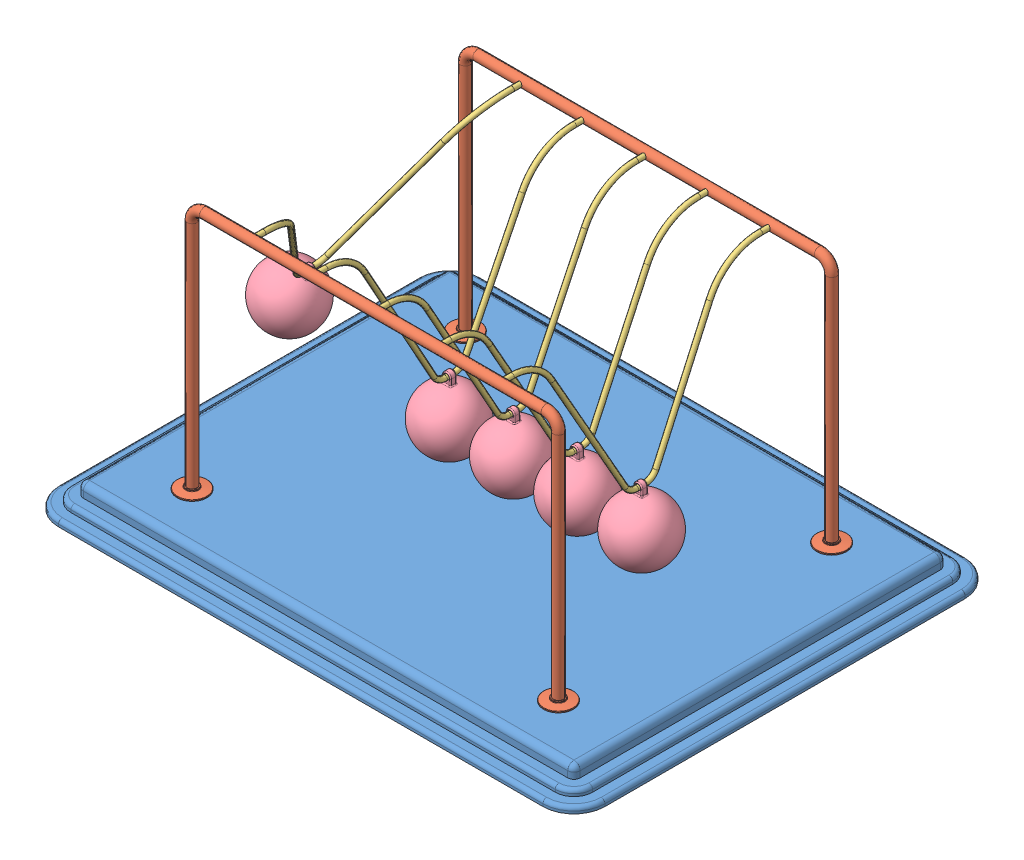
SolidWorks assembly Newtons Cradle NewtonsCradle 0249, configuration Default. Lengths in mm.
Overall size (440 222 340).
13 component instances, 4 part files, 34 mates.
Components (placement in the parent):
- Base 201,782820097245-1: Base 201,782820097245 [Default] at (-16.2968 -4.1587 11.425) size (440 20 340)
- frame NewtonsCradle 0249-1: frame NewtonsCradle 0249 [Default] at (-16.2968 144.4547 -98.575) size (319 202 24)
- frame NewtonsCradle 0249-2: frame NewtonsCradle 0249 [Default] at (-16.2968 144.4547 121.425) x (-1 0 0) z (0 0 -1) size (319 202 24)
- Hanging thing NewtonsCradle 0249-1: Hanging thing NewtonsCradle 0249 [Default] at (-157.6326 134.1825 11.425) x (0 0 1) z (-0.859985 0.510319 0) size (220 129 4)
- Hanging thing NewtonsCradle 0249-2: Hanging thing NewtonsCradle 0249 [Default] at (-66.576 122.8418 11.425) x (0 0 1) z (-0.999994 0.003446 0) size (220 129 4)
- Hanging thing NewtonsCradle 0249-3: Hanging thing NewtonsCradle 0249 [Default] at (-15.6923 122.8436 11.425) x (0 0 1) z (-0.999972 -0.007464 0) size (220 129 4)
- Hanging thing NewtonsCradle 0249-4: Hanging thing NewtonsCradle 0249 [Default] at (35.2213 122.8555 11.425) x (0 0 1) z (-0.999824 -0.018742 0) size (220 129 4)
- Hanging thing NewtonsCradle 0249-5: Hanging thing NewtonsCradle 0249 [Default] at (86.0287 122.8747 11.425) x (0 0 1) z (-0.999588 -0.028711 0) size (220 129 4)
- Sphere NewtonsCradle 0249-1: Sphere NewtonsCradle 0249 [Default] at (-195.3962 70.5436 11.425) x (0.859985 -0.510319 0) z (0 0 1) size (50 58.5 50)
- Sphere NewtonsCradle 0249-2: Sphere NewtonsCradle 0249 [Default] at (88.1533 48.9052 11.425) x (0.999588 0.028711 0) z (0 0 1) size (50 58.5 50)
- Sphere NewtonsCradle 0249-3: Sphere NewtonsCradle 0249 [Default] at (-15.14 48.8456 11.425) x (0.999972 0.007464 0) z (0 0 1) size (50 58.5 50)
- Sphere NewtonsCradle 0249-4: Sphere NewtonsCradle 0249 [Default] at (36.6081 48.8685 11.425) x (0.999824 0.018742 0) z (0 0 1) size (50 58.5 50)
- Sphere NewtonsCradle 0249-5: Sphere NewtonsCradle 0249 [Default] at (-66.831 48.8422 11.425) x (0.999994 -0.003446 0) z (0 0 1) size (50 58.5 50)
Mates (geometry in assembly coordinates):
- Coincident1: coincident anti-aligned: plane of Base-1 through (-211.2968 5.8413 156.425) normal (0 1 0); plane of frame-2 through (-175.7968 5.8413 121.425) normal (0 -1 0)
- Coincident2: coincident anti-aligned: plane of Base-1 through (-211.2968 5.8413 156.425) normal (0 1 0); plane of frame-1 through (143.2032 5.8413 -98.575) normal (0 -1 0)
- Concentric1: concentric anti-aligned: cylinder of frame-1 through (-116.2968 203.8413 -94.575) axis (0 0 -1) radius 2; cylinder of frame-2 through (-116.2968 203.8413 117.425) axis (0 0 1) radius 2
- Concentric2: concentric anti-aligned: cylinder of frame-1 through (83.7032 203.8413 -94.575) axis (0 0 -1) radius 2; cylinder of frame-2 through (83.7032 203.8413 117.425) axis (0 0 1) radius 2
- Distance1: distance = 60 mm: plane of frame-1 through (-16.2968 144.4547 -98.575) normal (0 0 1); line of Base-1 through (-211.2968 -12.1587 -158.575) axis (1 0 0)
- Distance2: distance = 60 mm: line of Base-1 through (178.7032 -12.1587 181.425) axis (-1 0 0); plane of frame-2 through (-16.2968 144.4547 121.425) normal (0 0 -1)
- Distance3: distance = 220 mm: plane of frame-2 through (-16.2968 144.4547 121.425) normal (-1 0 0); line of Base-1 through (-236.2968 -12.1587 156.425) axis (0 0 -1)
- Concentric3: concentric anti-aligned: cylinder of frame-1 through (-116.2968 203.8413 -94.575) axis (0 0 -1) radius 2; cylinder of Hanging thing-1 through (-116.2968 203.8413 111.425) axis (0 0 1) radius 2
- Concentric4: concentric anti-aligned: cylinder of frame-1 through (-116.2968 203.8413 -94.575) axis (0 0 -1) radius 2; cylinder of Hanging thing-1 through (-116.2968 203.8413 -98.575) axis (0 0 1) radius 2
- Concentric5: concentric aligned: cylinder of frame-2 through (-66.2968 203.8413 117.425) axis (0 0 1) radius 2; cylinder of Hanging thing-2 through (-66.2968 203.8413 111.425) axis (0 0 1) radius 2
- Concentric6: concentric aligned: cylinder of frame-2 through (-16.2968 203.8413 117.425) axis (0 0 1) radius 2; cylinder of Hanging thing-3 through (-16.2968 203.8413 111.425) axis (0 0 1) radius 2
- Concentric7: concentric aligned: cylinder of frame-2 through (33.7032 203.8413 117.425) axis (0 0 1) radius 2; cylinder of Hanging thing-4 through (33.7032 203.8413 111.425) axis (0 0 1) radius 2
- Concentric8: concentric aligned: cylinder of frame-2 through (83.7032 203.8413 117.425) axis (0 0 1) radius 2; cylinder of Hanging thing-5 through (83.7032 203.8413 111.425) axis (0 0 1) radius 2
- Coincident5: coincident anti-aligned: plane of frame-2 through (83.7032 203.8413 121.425) normal (0 0 -1); plane of Hanging thing-5 through (83.7032 203.8413 121.425) normal (0 0 1)
- Coincident6: coincident anti-aligned: plane of frame-2 through (33.7032 203.8413 121.425) normal (0 0 -1); plane of Hanging thing-4 through (33.7032 203.8413 121.425) normal (0 0 1)
- Coincident7: coincident anti-aligned: plane of frame-2 through (-16.2968 203.8413 121.425) normal (0 0 -1); plane of Hanging thing-3 through (-16.2968 203.8413 121.425) normal (0 0 1)
- Coincident8: coincident anti-aligned: plane of frame-2 through (-66.2968 203.8413 121.425) normal (0 0 -1); plane of Hanging thing-2 through (-66.2968 203.8413 121.425) normal (0 0 1)
- Coincident9: coincident anti-aligned: plane of frame-2 through (-116.2968 203.8413 121.425) normal (0 0 -1); plane of Hanging thing-1 through (-116.2968 203.8413 121.425) normal (0 0 1)
- Concentric9: concentric anti-aligned: cylinder of Hanging thing-1 through (-117.0163 78.8434 7.925) axis (0 0 1) radius 2; cylinder of Sphere-1 through (-117.0163 78.8434 13.925) axis (0 0 -1) radius 2
- Concentric13: concentric anti-aligned: cylinder of Hanging thing-2 through (-66.7276 78.842 7.925) axis (0 0 1) radius 2; cylinder of Sphere-5 through (-66.7276 78.842 13.925) axis (0 0 -1) radius 2
- Concentric15: concentric anti-aligned: cylinder of Hanging thing-3 through (-15.3639 78.8448 7.925) axis (0 0 1) radius 2; cylinder of Sphere-3 through (-15.3639 78.8448 13.925) axis (0 0 -1) radius 2
- Concentric16: concentric anti-aligned: cylinder of Hanging thing-5 through (87.292 78.8928 7.925) axis (0 0 1) radius 2; cylinder of Sphere-2 through (87.292 78.8928 13.925) axis (0 0 -1) radius 2
- Concentric17: concentric anti-aligned: cylinder of Hanging thing-4 through (36.0459 78.8632 7.925) axis (0 0 1) radius 2; cylinder of Sphere-4 through (36.0459 78.8632 13.925) axis (0 0 -1) radius 2
- Parallel1: parallel anti-aligned: plane of Hanging thing-1; plane of Sphere-1
- Coincident22: coincident anti-aligned: plane of Hanging thing-1; plane of Sphere-1
- Coincident12: coincident aligned: plane of Hanging thing-2 through (-66.576 122.8418 11.425) normal (0 0 1); plane of Sphere-5 through (-66.831 48.8422 11.425) normal (0 0 1)
- Coincident10: coincident aligned: plane of Hanging thing-1 through (-116.763 122.8426 11.425) normal (0 0 1); plane of Sphere-1 through (-118.5806 48.8842 11.425) normal (0 0 1)
- Coincident13: coincident anti-aligned: plane of Hanging thing-2 through (-66.576 122.8418 11.425) normal (-0.999994 0.003446 0); plane of Sphere-5 through (-66.831 48.8422 11.425) normal (0.999994 -0.003446 0)
- Coincident14: coincident anti-aligned: plane of Hanging thing-3 through (-15.6923 122.8436 11.425) normal (-0.999972 -0.007464 0); plane of Sphere-3 through (-15.14 48.8456 11.425) normal (0.999972 0.007464 0)
- Coincident15: coincident aligned: plane of Hanging thing-3 through (-15.6923 122.8436 11.425) normal (0 0 1); plane of Sphere-3 through (-15.14 48.8456 11.425) normal (0 0 1)
- Coincident18: coincident aligned: plane of Hanging thing-4 through (35.2213 122.8555 11.425) normal (0 0 1); plane of Sphere-4 through (36.6081 48.8685 11.425) normal (0 0 1)
- Coincident19: coincident anti-aligned: plane of Hanging thing-4 through (35.2213 122.8555 11.425) normal (-0.999824 -0.018742 0); plane of Sphere-4 through (36.6081 48.8685 11.425) normal (0.999824 0.018742 0)
- Coincident20: coincident anti-aligned: plane of Hanging thing-5 through (86.0287 122.8747 11.425) normal (-0.999588 -0.028711 0); plane of Sphere-2 through (88.1533 48.9052 11.425) normal (0.999588 0.028711 0)
- Coincident21: coincident aligned: plane of Hanging thing-5 through (86.0287 122.8747 11.425) normal (0 0 1); plane of Sphere-2 through (88.1533 48.9052 11.425) normal (0 0 1)
